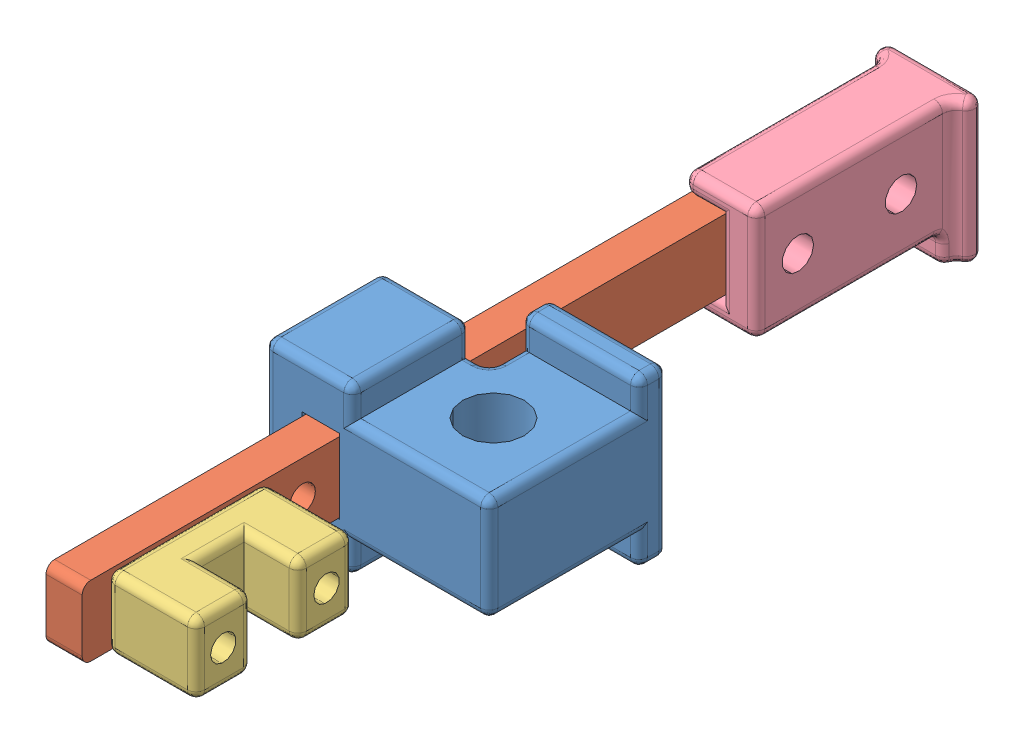
SolidWorks assembly On_Off Switch, configuration Default. Lengths in mm.
Overall size (19.94 15.11 75.63).
4 component instances, 4 part files, 9 mates.
Components (placement in the parent):
- Switch Bracket-1: Switch Bracket [Default] at (5.8821 6.3417 11.9505) size (19.94 14.73 15.81)
- Switch_Latch Arm-1: Switch_Latch Arm [Default] at (-1.1664 3.1032 -31.674) x (0 0 1) z (-1 0 0) size (73.03 6.22 3.2)
- Switch Latch-1: Switch Latch [Default] at (-1.1664 3.0397 25.222) x (0 0 1) z (-1 0 0) size (13.97 6.35 7.94)
- Switch Knob-2: Switch Knob [Default] at (3.2532 11.2947 -34.2775) x (0 0 1) z (1 0 0) size (19.05 12.7 8.45)
Mates (geometry in assembly coordinates):
- Distance1: distance = 0.0635 mm: plane of Switch_Latch Arm-1 through (-1.1664 3.1032 -31.674) normal (1 0 0); plane of Switch Bracket-1 through (-1.1029 9.6437 26.0015) normal (-1 0 0)
- Distance2: distance = 0.0635 mm: plane of Switch Bracket-1 through (-1.1029 3.0397 26.0015) normal (0 1 0); plane of Switch_Latch Arm-1 through (-4.3668 3.1032 -31.674) normal (0 -1 0)
- Coincident3: coincident: plane of Switch_Latch Arm-1 through (-1.1664 3.1032 -31.674) normal (1 0 0); plane of Switch Latch-1 through (-1.1664 9.3897 25.222) normal (-1 0 0)
- Concentric1: concentric: cylinder of Switch_Latch Arm-1 through (-4.3668 6.2147 27.635) axis (1 0 0) radius 1.27; cylinder of Switch Latch-1 through (9.9681 6.2147 27.635) axis (-1 0 0) radius 1.1303
- Concentric2: concentric: cylinder of Switch_Latch Arm-1 through (-4.3668 6.2147 36.779) axis (1 0 0) radius 1.27; cylinder of Switch Latch-1 through (9.9681 6.2147 36.779) axis (-1 0 0) radius 1.1303
- Distance5: distance = 15.494 mm: cylinder of Switch Bracket-1 through (5.8821 10.9772 11.9505) axis (0 -1 0) radius 2.7305; plane of Switch Latch-1 through (6.7711 9.3897 30.175) normal (0 0 1)
- Concentric3: concentric: cylinder of Switch_Latch Arm-1 through (-4.3668 6.2147 -18.9105) axis (1 0 0) radius 1.1303; cylinder of Switch Knob-2 through (5.9345 6.2147 -18.9105) axis (-1 0 0) radius 1.397
- Concentric4: concentric: cylinder of Switch_Latch Arm-1 through (-4.3668 6.2147 -28.0545) axis (1 0 0) radius 1.1303; cylinder of Switch Knob-2 through (5.9345 6.2147 -28.0545) axis (-1 0 0) radius 1.397
- Coincident4: coincident: plane of Switch_Latch Arm-1 through (-1.1664 3.1032 -31.674) normal (1 0 0); plane of Switch Knob-2 through (-1.1664 2.9762 -31.7375) normal (-1 0 0)
